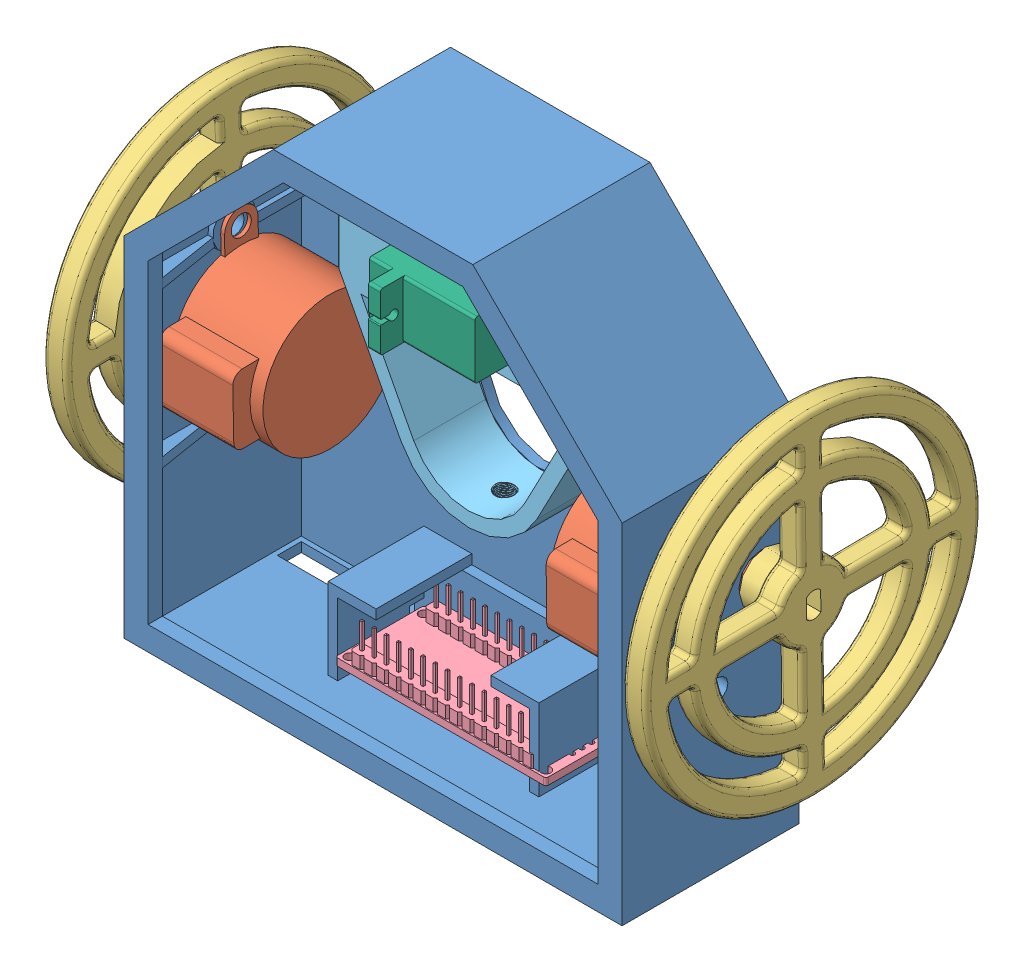
SolidWorks assembly Assemblage1, configuration Défaut. Lengths in mm.
Overall size (126.19 104 71.3).
8 component instances, 6 part files, 18 mates.
Components (placement in the parent):
- chassis v2-1: chassis v2 [Défaut] at (-16.2971 4.8671 -16.5) size (104 104 37)
- Moteur-pap-Arduino-1: Moteur-pap-Arduino [Défaut] at (-46.2971 1.605 -2.5014) x (0 0.999823 0.018816) z (0 -0.018816 0.999823) size (42 29 31.5)
- Roue-1: Roue [Défaut] at (41.7029 1.9031 -10.4984) x (0 -0.999939 -0.011012) z (1 0 0) size (70 70 10.1)
- Moteur-pap-Arduino-2: Moteur-pap-Arduino [Défaut] at (13.7029 1.6674 -2.5005) x (0 -0.999939 -0.011012) z (0 -0.011012 0.999939) size (42 29 31.5)
- Roue-2: Roue [Défaut] at (-74.2971 1.2307 -10.5349) x (0 -0.999823 -0.018816) z (-1 0 0) size (70 70 10.1)
- arduino nano-1: arduino nano [Default] at (-14.2971 -40.5129 -2.8689) x (1 0 0) z (0 0 -1) size (45.25 13.5 18.5)
- attache crayon-1: attache crayon [Défaut] at (-16.2971 4.8671 -1.5) x (1 0 0) z (0 0 -1) size (54.71 56 15)
- Towerpro Micro Servo 9g (1)-1: Towerpro Micro Servo 9g (1) [Varsayılan] at (-2.7844 33.7148 -0.5) x (0 1 0) z (0 0 1) size (12 30 32)
Mates (geometry in assembly coordinates):
- Coaxiale1: concentric: cylinder of chassis v2-1 through (35.7029 1.7555 -10.5) axis (-1 0 0) radius 4.6; cylinder of Moteur-pap-Arduino-1 through (-66.7971 1.7555 -10.5) axis (1 0 0) radius 4.6
- Coïncidente1: coincident: plane of chassis v2-1 through (-65.2971 19.2555 -1.5) normal (1 0 0); plane of Moteur-pap-Arduino-1 through (-65.2971 1.605 -2.5014) normal (-1 0 0)
- Coaxiale2: concentric: cylinder of chassis v2-1 through (35.7029 1.7555 -10.5) axis (-1 0 0) radius 4.6; cylinder of Moteur-pap-Arduino-2 through (34.2029 1.7555 -10.5) axis (-1 0 0) radius 4.6
- Coïncidente2: coincident: plane of chassis v2-1 through (32.7029 -14.3329 -1.5) normal (-1 0 0); plane of Moteur-pap-Arduino-2 through (32.7029 1.6674 -2.5005) normal (1 0 0)
- Coïncidente9: coincident: line of Roue-1 through (36.7029 -0.1133 -9.0205) axis (0 0.999939 0.011012); line of Moteur-pap-Arduino-2 through (36.7029 -0.2609 -9.0221) axis (0 0.999939 0.011012)
- Coïncidente10: coincident: plane of Roue-1 through (46.7029 1.9196 -11.9983) normal (0 -0.011012 0.999939); plane of Moteur-pap-Arduino-2 through (36.7029 7.9957 -11.9314) normal (0 0.011012 -0.999939)
- Tangent3: tangent: cylinder of Roue-1 through (46.7029 1.378 -10.5292) axis (-1 0 0) radius 2.1213; cylinder of Moteur-pap-Arduino-2 through (42.7029 1.7555 -10.5) axis (-1 0 0) radius 2.5
- Coïncidente11: coincident: plane of Moteur-pap-Arduino-1 through (-69.2971 1.605 -2.5014) normal (-1 0 0); circle of Roue-2
- Parallèle6: parallel: line of Moteur-pap-Arduino-1 through (-75.2971 -0.2159 -12.0374) axis (0 0.999823 0.018816); line of Roue-2 through (-79.2971 3.2586 -11.997) axis (0 -0.999823 -0.018816)
- Coaxiale7: concentric: cylinder of Moteur-pap-Arduino-1 through (-75.2971 1.7555 -10.5) axis (1 0 0) radius 2.5; cylinder of Roue-2 through (-79.2971 1.7555 -10.5) axis (1 0 0) radius 2.1213
- Coïncidente18: coincident: plane of chassis v2-1 through (-16.2971 4.8671 -12.1189) normal (0 0 1); plane of arduino nano-1 through (-36.2971 -42.0129 -12.1189) normal (0 0 -1)
- Coïncidente20: coincident: plane of chassis v2-1 through (-36.2971 -45.1329 -12.1189) normal (1 0 0); plane of arduino nano-1 through (-36.2971 -42.0129 -12.1189) normal (-1 0 0)
- Coïncidente24: coincident: plane of chassis v2-1 through (-16.2971 4.8671 -16.5) normal (0 0 1); plane of attache crayon-1 through (-16.2971 4.8671 -16.5) normal (0 0 -1)
- Parallèle12: parallel: plane of chassis v2-1 through (-36.2971 54.8671 18.5) normal (0 -1 0); plane of attache crayon-1 through (-43.7844 22.8671 -16.5) normal (0 1 0)
- Coaxiale8: concentric: circle of chassis v2-1; circle of attache crayon-1
- Coïncidente27: coincident: plane of chassis v2-1 through (-16.2971 4.8671 -16.5) normal (0 0 1); plane of Towerpro Micro Servo 9g (1)-1 through (-20.2844 28.2148 -16.5) normal (0 0 -1)
- Parallèle13: parallel: line of attache crayon-1 through (-28.7844 44.4671 -1.9) axis (0 -1 0); line of Towerpro Micro Servo 9g (1)-1 through (-24.7844 28.2148 10.75) axis (0 1 0)
- Coïncidente29: coincident: plane of attache crayon-1 through (-28.7844 44.8671 -1.5) normal (1 0 0); plane of Towerpro Micro Servo 9g (1)-1 through (-28.7844 33.7148 -2.75) normal (-1 0 0)
